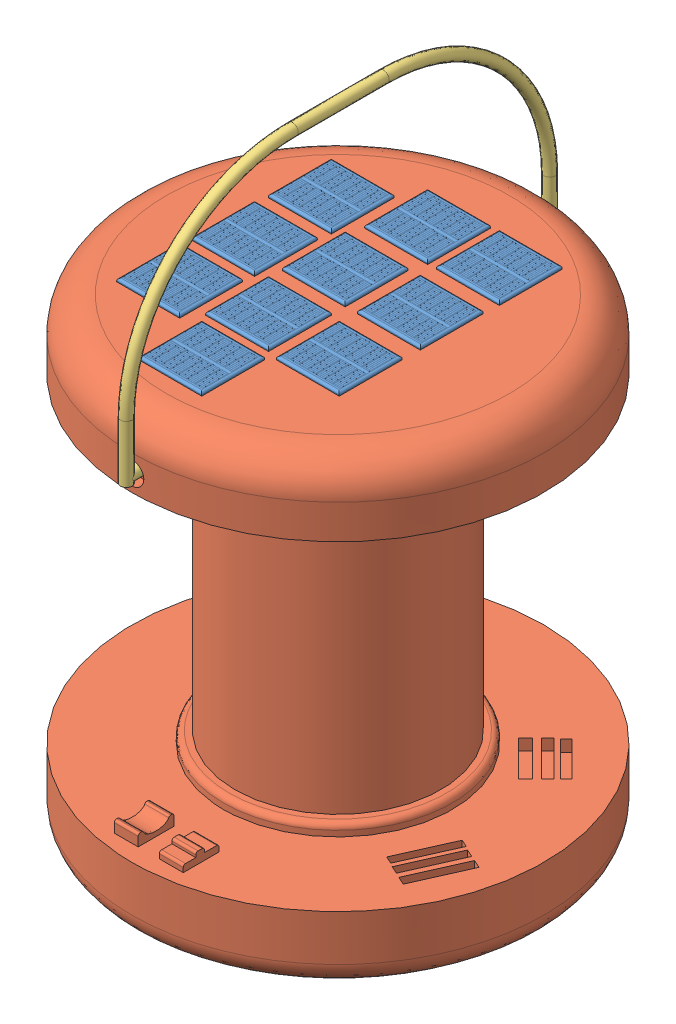
SolidWorks assembly Angaza Lamp Assemble, configuration Default. Lengths in mm.
Overall size (360 550.17 380).
12 component instances, 3 part files, 2 mates.
Components (placement in the parent):
- Polycrystalline Solar Panel, 3-4 V, 60 mA - 250 mA-1: Polycrystalline Solar Panel, 3-4 V, 60 mA - 250 mA [CNC55X55-4, 60 mA] at (19.1722 29.4272 42.6189) size (55 3.32 55)
- Angaza Lamp-1: Angaza Lamp [Default] at (-32.161 -371.9728 132.3951) size (360 400 360)
- Polycrystalline Solar Panel, 3-4 V, 60 mA - 250 mA-2: Polycrystalline Solar Panel, 3-4 V, 60 mA - 250 mA [CNC55X55-4, 60 mA] at (-41.0206 31.6127 45.1443) size (55 3.32 55)
- Polycrystalline Solar Panel, 3-4 V, 60 mA - 250 mA-3: Polycrystalline Solar Panel, 3-4 V, 60 mA - 250 mA [CNC55X55-4, 60 mA] at (-44.9772 31.6127 113.2425) size (55 3.32 55)
- Polycrystalline Solar Panel, 3-4 V, 60 mA - 250 mA-4: Polycrystalline Solar Panel, 3-4 V, 60 mA - 250 mA [CNC55X55-4, 60 mA] at (-44.6983 31.6127 180.5724) size (55 3.32 55)
- Polycrystalline Solar Panel, 3-4 V, 60 mA - 250 mA-6: Polycrystalline Solar Panel, 3-4 V, 60 mA - 250 mA [CNC55X55-4, 60 mA] at (20.5691 31.6127 113.1343) size (55 3.32 55)
- Polycrystalline Solar Panel, 3-4 V, 60 mA - 250 mA-7: Polycrystalline Solar Panel, 3-4 V, 60 mA - 250 mA [CNC55X55-4, 60 mA] at (20.0103 31.6127 183.4172) size (55 3.32 55)
- Polycrystalline Solar Panel, 3-4 V, 60 mA - 250 mA-8: Polycrystalline Solar Panel, 3-4 V, 60 mA - 250 mA [CNC55X55-4, 60 mA] at (-106.1926 31.6127 64.1911) size (55 3.32 55)
- Polycrystalline Solar Panel, 3-4 V, 60 mA - 250 mA-9: Polycrystalline Solar Panel, 3-4 V, 60 mA - 250 mA [CNC55X55-4, 60 mA] at (-107.6619 31.6127 129.8066) size (55 3.32 55)
- Polycrystalline Solar Panel, 3-4 V, 60 mA - 250 mA-10: Polycrystalline Solar Panel, 3-4 V, 60 mA - 250 mA [CNC55X55-4, 60 mA] at (-108.791 31.6127 194.1523) size (55 3.32 55)
- Polycrystalline Solar Panel, 3-4 V, 60 mA - 250 mA-11: Polycrystalline Solar Panel, 3-4 V, 60 mA - 250 mA [CNC55X55-4, 60 mA] at (-40.0977 31.6127 243.5252) size (55 3.32 55)
- Handle-1: Handle [Default] at (-32.161 -22.0834 132.3951) size (10 200.28 380)
Mates (geometry in assembly coordinates):
- Concentric2: concentric aligned: circle of Angaza Lamp-1; circle of Handle-1
- Coincident2: coincident anti-aligned: plane of Angaza Lamp-1 through (-32.161 -16.9728 -37.6049) normal (0 0 -1); plane of Handle-1 through (-32.161 -16.9728 -37.6049) normal (0 0 1)
